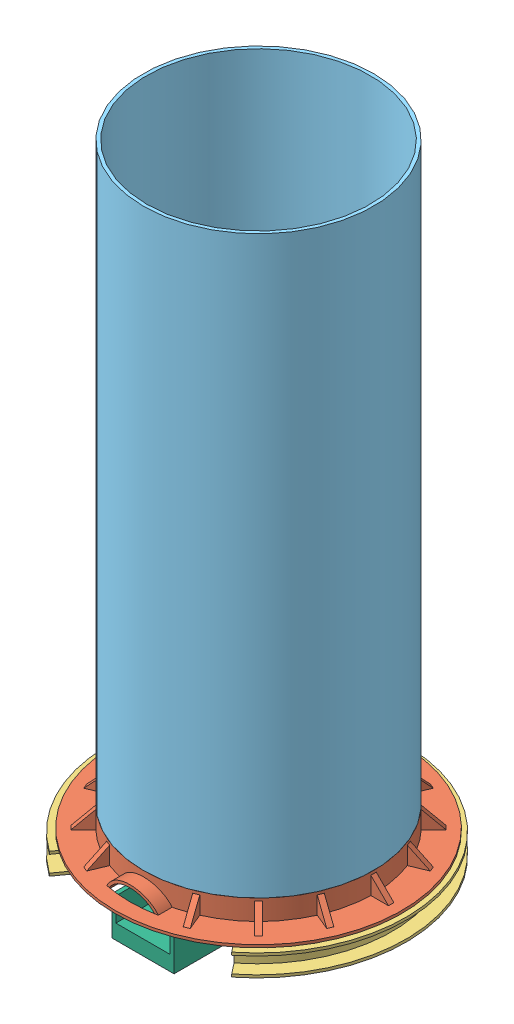
SolidWorks assembly ASSY-RECOVERY, configuration Default. Lengths in mm.
Overall size (220 489.5 216).
7 component instances, 6 part files, 0 mates.
Components (placement in the parent):
- CUT-LOOP-1: CUT-LOOP [Default] at (0 0 -13.9988) size (81 126.36 10.2)
- CAP-1: CAP [Default] at (1.1 0 0) size (212 47 212)
- V-BAND-1: V-BAND [Default] at origin size (220 16 199.44)
- LINE-CUTTER-1: LINE-CUTTER [Default] at (3 11 -13.9988) size (23 17 83)
- MAIN-CYLINDER-1: MAIN-CYLINDER [Default] at origin size (170 425 170)
- LINE-CUTTER-2: LINE-CUTTER [Default] at (80 11 -13.9988) size (23 17 83)
- BASEPLATE-1: BASEPLATE [Default] at origin size (46 51 175.2)
